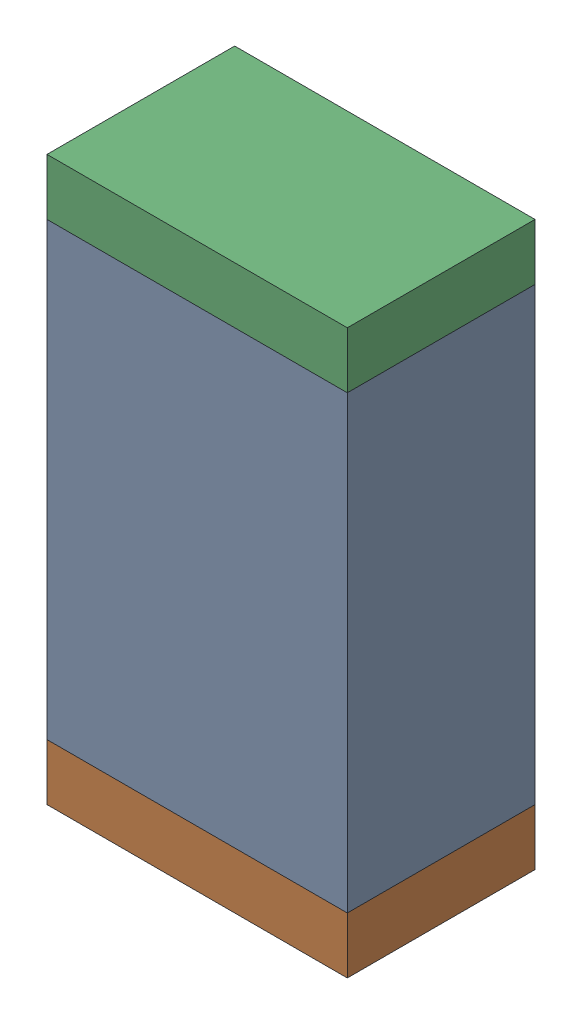
SolidWorks assembly R63, configuration Default. Lengths in mm.
Overall size (0.8 1.5 0.5).
6 component instances, 2 part files, 0 mates.
Components (placement in the parent):
- 810156976-1: 810156976 [Default] at (111.5 73.7 0) size (0.8 1.2 0.5)
  - Extruded_6-1: Extruded_6 [Default] at origin size (0.8 1.2 0.5)
- 810156592-1: 810156592 [Default] at (111.5 73.025 0) size (0.8 0.15 0.5)
  - Extruded_7-1: Extruded_7 [Default] at origin size (0.8 0.15 0.5)
- 810156592-2: 810156592 [Default] at (111.5 74.375 0) size (0.8 0.15 0.5)
  - Extruded_7-1: Extruded_7 [Default] at origin size (0.8 0.15 0.5)
